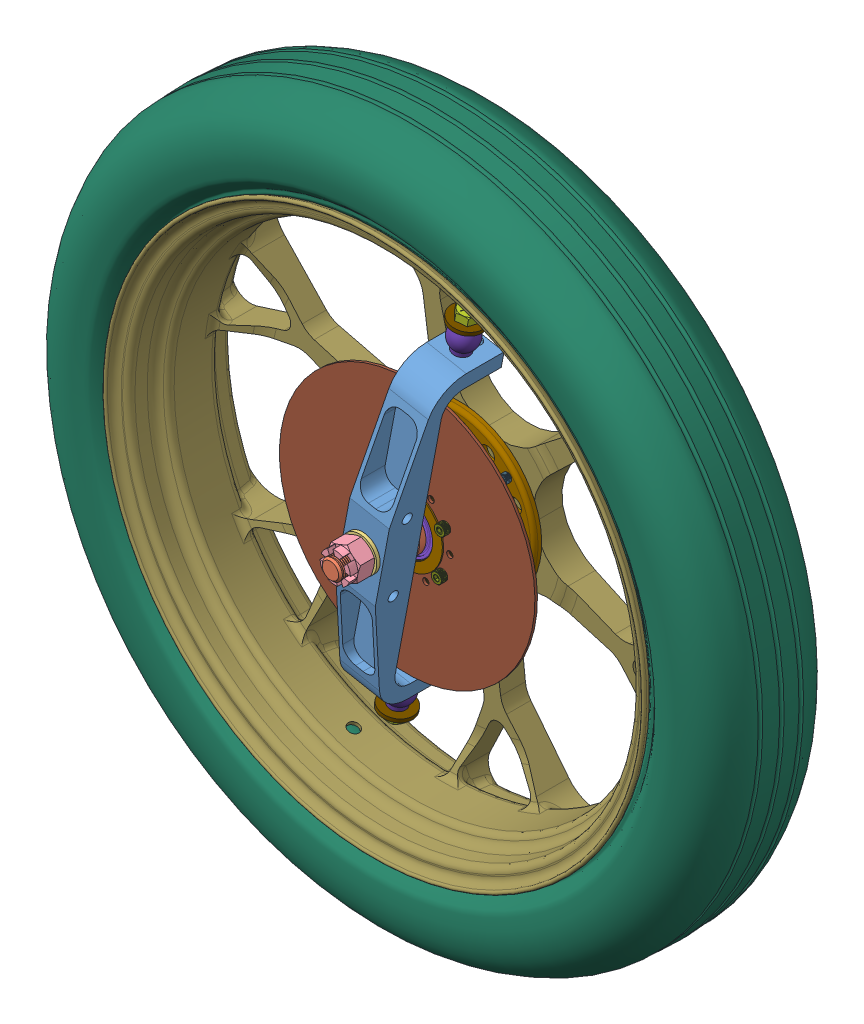
SolidWorks assembly SpindleAssy, configuration Default. Lengths in mm.
Overall size (616.2 616.2 50000).
36 component instances, 18 part files, 73 mates.
Components (placement in the parent):
- Knuckle-1: Knuckle [Default] at (82.0121 130.0239 204.0915) size (78.12 253.33 73.5)
- Spindle_Light-1: Spindle_Light [Default] at (82.0121 130.0239 204.0915) x (0 0 -1) z (0.185408 0.982662 0) size (140.5 34 30)
- M16 98688A121_General Purpose Zinc-Plated Steel Washer-1: M16 98688A121_General Purpose Zinc-Plated Steel Washer [98688A121] at (82.0121 130.0239 232.5915) x (0.99983 -0.018445 0) z (0 0 1) size (28 28 2.7)
- M16x1-5 93760A128_Steel Locknut for Use with Cotter Pins-1: M16x1-5 93760A128_Steel Locknut for Use with Cotter Pins [93760A128] at (82.0121 130.0239 254.2915) x (0.982886 -0.184217 0) z (0 0 1) size (24 27.71 19.76)
- M14 98689A119_General Purpose 18-8 Stainless Steel Washer-1: M14 98689A119_General Purpose 18-8 Stainless Steel Washer [98689A119] at (82.0121 130.0239 138.2415) size (24 24 2.7)
- M14x1-5 93760A127_Steel Locknut for Use with Cotter Pins-1: M14x1-5 93760A127_Steel Locknut for Use with Cotter Pins [93760A127] at (82.0121 130.0239 120.8915) x (-0.661913 -0.74958 0) z (0 0 -1) size (22 25.4 16.76)
- 91257A659_Zinc Yellow-Chromate Plated Hex Head Screw-2: 91257A659_Zinc Yellow-Chromate Plated Hex Head Screw [91257A659] at (58.1191 3.3909 177.4439) x (0.185408 0.982662 0) z (0.110595 -0.020867 0.993646) size (57.6 16.5 14.29)
- 91257A659_Zinc Yellow-Chromate Plated Hex Head Screw-3: 91257A659_Zinc Yellow-Chromate Plated Hex Head Screw [91257A659] at (105.9051 256.6568 177.4439) x (-0.185408 -0.982662 0) z (-0.685297 0.129301 0.716693) size (57.6 16.5 14.29)
- SKF_6004-2Z.stp-1: SKF_6004-2Z.stp [Default] at (82.0121 130.0239 185.0915) x (0 0 1) z (-0.58163 0.813454 0) size (12 42 42)
- Hub5-16-1: Hub5-16 [Default] at (82.0121 130.0239 173.6746) x (-0.944813 0.32761 0) z (0.32761 0.944813 0) size (130 85 130)
- SKF_6003-2Z.stp-1: SKF_6003-2Z.stp [Default] at (82.0121 130.0239 149.5915) x (0 0 -1) z (0.973183 -0.230032 0) size (10 35 35)
- BasicBrakeDisc-1: BasicBrakeDisc [Default] at (82.0121 130.0239 195.0915) x (0.071911 0.997411 0) z (0 0 1) size (190.5 190.5 3.17)
- rimmachined v13.2-1: rimmachined v13.2 [Default] at (82.0121 130.0239 177.3915) x (0 0 -1) z (-0.981935 -0.189217 0) size (93.59 431.57 431.57)
- 92415A381_Zinc-Plated Steel Unthreaded Spacer-2: 92415A381_Zinc-Plated Steel Unthreaded Spacer [92415A381] at (71.0682 186.982 155.2387) size (7.94 7.94 7.21)
- 92415A381_Zinc-Plated Steel Unthreaded Spacer-3: 92415A381_Zinc-Plated Steel Unthreaded Spacer [92415A381] at (27.2129 149.0252 155.2387) size (7.94 7.94 7.21)
- 92415A381_Zinc-Plated Steel Unthreaded Spacer-4: 92415A381_Zinc-Plated Steel Unthreaded Spacer [92415A381] at (38.1569 92.0671 155.2387) size (7.94 7.94 7.21)
- 92415A381_Zinc-Plated Steel Unthreaded Spacer-5: 92415A381_Zinc-Plated Steel Unthreaded Spacer [92415A381] at (92.956 73.0657 155.2387) size (7.94 7.94 7.21)
- 92415A381_Zinc-Plated Steel Unthreaded Spacer-6: 92415A381_Zinc-Plated Steel Unthreaded Spacer [92415A381] at (136.8113 111.0225 155.2387) size (7.94 7.94 7.21)
- 92415A381_Zinc-Plated Steel Unthreaded Spacer-7: 92415A381_Zinc-Plated Steel Unthreaded Spacer [92415A381] at (125.8674 167.9807 155.2387) size (7.94 7.94 7.21)
- 8-32x3-8 92196A192_18-8 Stainless Steel Socket Head Screw-1: 8-32x3-8 92196A192_18-8 Stainless Steel Socket Head Screw [92196A192] at (92.956 73.0657 158.4118) size (6.85 6.85 14.15)
- 8-32x3-8 92196A192_18-8 Stainless Steel Socket Head Screw-2: 8-32x3-8 92196A192_18-8 Stainless Steel Socket Head Screw [92196A192] at (38.1569 92.0671 158.4118) size (6.85 6.85 14.15)
- 8-32x3-8 92196A192_18-8 Stainless Steel Socket Head Screw-3: 8-32x3-8 92196A192_18-8 Stainless Steel Socket Head Screw [92196A192] at (136.8113 111.0225 158.4118) size (6.85 6.85 14.15)
- 8-32x3-8 92196A192_18-8 Stainless Steel Socket Head Screw-4: 8-32x3-8 92196A192_18-8 Stainless Steel Socket Head Screw [92196A192] at (125.8674 167.9807 158.4118) size (6.85 6.85 14.15)
- 8-32x3-8 92196A192_18-8 Stainless Steel Socket Head Screw-5: 8-32x3-8 92196A192_18-8 Stainless Steel Socket Head Screw [92196A192] at (71.0682 186.982 158.4118) size (6.85 6.85 14.15)
- 8-32x3-8 92196A192_18-8 Stainless Steel Socket Head Screw-6: 8-32x3-8 92196A192_18-8 Stainless Steel Socket Head Screw [92196A192] at (27.2129 149.0252 158.4118) size (6.85 6.85 14.15)
- Michelin Tire-1: Michelin Tire [Default] at (82.0121 130.0239 177.3915) x (0 0 1) z (-0.993534 -0.113534 0) size (101.13 556.61 556.61)
- M5x10 91290A224_Alloy Steel Socket Head Screw-1: M5x10 91290A224_Alloy Steel Socket Head Screw [91290A224] at (84.4571 163.9358 194.5915) x (0.901899 0.431946 0) z (0 0 1) size (8.5 8.5 15.31)
- M5x10 91290A224_Alloy Steel Socket Head Screw-2: M5x10 91290A224_Alloy Steel Socket Head Screw [91290A224] at (53.866 149.0973 194.5915) x (-0.609316 -0.792927 0) z (0 0 1) size (8.5 8.5 15.31)
- M5x10 91290A224_Alloy Steel Socket Head Screw-3: M5x10 91290A224_Alloy Steel Socket Head Screw [91290A224] at (112.6032 144.8625 194.5915) x (0.740699 0.671837 0) z (0 0 1) size (8.5 8.5 15.31)
- M5x10 91290A224_Alloy Steel Socket Head Screw-4: M5x10 91290A224_Alloy Steel Socket Head Screw [91290A224] at (110.1583 110.9505 194.5915) x (-0.161403 -0.986889 0) z (0 0 1) size (8.5 8.5 15.31)
- M5x10 91290A224_Alloy Steel Socket Head Screw-5: M5x10 91290A224_Alloy Steel Socket Head Screw [91290A224] at (51.421 115.1853 194.5915) x (0.079005 -0.996874 0) z (0 0 1) size (8.5 8.5 15.31)
- M5x10 91290A224_Alloy Steel Socket Head Screw-6: M5x10 91290A224_Alloy Steel Socket Head Screw [91290A224] at (79.5671 96.1119 194.5915) x (-0.159143 -0.987256 0) z (0 0 1) size (8.5 8.5 15.31)
- BallSuper-Swivel  Joint Rod End6960T231_-1: BallSuper-Swivel  Joint Rod End6960T231_ [6960T231] at (75.3125 -8.1245 178.3098) x (-0.044663 0.008427 0.998967) z (-0.185408 -0.982662 0) size (20.64 20.64 22.23)
- BallSuper-Swivel  Joint Rod End6960T231_-2: BallSuper-Swivel  Joint Rod End6960T231_ [6960T231] at (109.0836 264.3285 196.4178) x (0.978736 -0.184667 -0.089292) z (0.185408 0.982662 0) size (20.64 20.64 22.23)
- 3-8 98029A046_Black-Oxide Steel Oversized Washer-1: 3-8 98029A046_Black-Oxide Steel Oversized Washer [98029A046] at (54.2751 -16.9823 177.4439) x (0.965511 -0.182172 -0.186017) z (0.185408 0.982662 0) size (25.4 25.4 2.98)
- 3-8 98029A046_Black-Oxide Steel Oversized Washer-2: 3-8 98029A046_Black-Oxide Steel Oversized Washer [98029A046] at (109.7491 277.0301 177.4439) x (0.965511 -0.182172 -0.186017) z (0.185408 0.982662 0) size (25.4 25.4 2.98)
Mates (geometry in assembly coordinates):
- Coincident1: coincident anti-aligned: circle of Knuckle-1; circle of Spindle_Light-1
- Concentric1: concentric aligned: circle of Knuckle-1; circle of M16 98688A121_General Purpose Zinc-Plated Steel Washer-1
- Concentric2: concentric aligned: circle of M16 98688A121_General Purpose Zinc-Plated Steel Washer-1; circle of M16x1-5 93760A128_Steel Locknut for Use with Cotter Pins-1
- Coincident2: coincident anti-aligned: plane of Knuckle-1 through (82.0121 130.0239 232.5915) normal (0 0 1); plane of M16 98688A121_General Purpose Zinc-Plated Steel Washer-1 through (82.0121 130.0239 232.5915) normal (0 0 -1)
- Coincident3: coincident anti-aligned: plane of M16 98688A121_General Purpose Zinc-Plated Steel Washer-1 through (82.0121 130.0239 235.2915) normal (0 0 1); plane of M16x1-5 93760A128_Steel Locknut for Use with Cotter Pins-1 through (84.5647 143.6431 235.2915) normal (0 0 -1)
- Parallel1: parallel aligned: plane of Spindle_Light-1 through (82.0121 130.0239 258.0915) normal (0 0 1); plane of M16x1-5 93760A128_Steel Locknut for Use with Cotter Pins-1 through (82.0121 130.0239 248.2915) normal (0 0 1)
- Concentric3: concentric anti-aligned: circle of M14 98689A119_General Purpose 18-8 Stainless Steel Washer-1; circle of M14x1-5 93760A127_Steel Locknut for Use with Cotter Pins-1
- Coincident5: coincident anti-aligned: plane of M14 98689A119_General Purpose 18-8 Stainless Steel Washer-1 through (82.0121 130.0239 136.8915) normal (0 0 -1); plane of M14x1-5 93760A127_Steel Locknut for Use with Cotter Pins-1 through (75.0117 150.8804 136.8915) normal (0 0 1)
- Concentric4: concentric anti-aligned: circle of Spindle_Light-1; circle of M14 98689A119_General Purpose 18-8 Stainless Steel Washer-1
- Perpendicular1: perpendicular: line of Knuckle-1 through (84.6232 230.1587 204.0915) axis (-0.185408 -0.982662 0); line of Spindle_Light-1 through (76.9319 146.2471 204.0915) axis (0.982662 -0.185408 0)
- Concentric5: concentric aligned: circle of Knuckle-1; circle of Super-Swivel Ball Joint Ball End2-1
- Coincident7: coincident anti-aligned: plane of Knuckle-1 through (89.6292 256.6906 232.5915) normal (0.185408 0.982662 0); plane of Super-Swivel Ball Joint Ball End2-1 through (107.5018 254.0508 172.0915) normal (-0.20131 -0.979528 0)
- Concentric6: concentric anti-aligned: circle of Knuckle-1; circle of Super-Swivel Ball Joint Ball End2-2
- Coincident8: coincident anti-aligned: plane of Knuckle-1 through (74.395 3.3572 232.5915) normal (-0.185408 -0.982662 0); plane of Super-Swivel Ball Joint Ball End2-2 through (56.5224 5.997 172.0915) normal (0.20131 0.979528 0)
- Coincident11: coincident anti-aligned: circle of Knuckle-1; circle of SteerArm-1
- Coincident12: coincident anti-aligned: circle of Knuckle-1; circle of SteerArm-1
- Concentric7: concentric anti-aligned: circle of Spindle_Light-1; circle of SKF_6004-2Z.stp-1
- Coincident13: coincident anti-aligned: plane of Spindle_Light-1 through (70.2202 132.2488 197.0915) normal (0 0 -1); plane of SKF_6004-2Z.stp-1 through (90.6347 136.1891 197.0915) normal (0 0 1)
- Coincident14: coincident anti-aligned: plane of SKF_6004-2Z.stp-1 through (98.6066 141.8891 185.0915) normal (0 0 -1); plane of Hub5-16-1 through (64.0607 136.2485 185.0915) normal (0 0 1)
- Concentric8: concentric aligned: cylinder of SKF_6004-2Z.stp-1 through (82.0121 130.0239 235.0915) axis (0 0 1) radius 21; cylinder of Hub5-16-1 through (82.0121 130.0239 1099.7023) axis (0 0 1) radius 21
- Concentric9: concentric anti-aligned: cylinder of Hub5-16-1 through (82.0121 130.0239 1099.7023) axis (0 0 1) radius 17.5; cylinder of SKF_6003-2Z.stp-1 through (82.0121 130.0239 99.5915) axis (0 0 -1) radius 17.5
- Coincident15: coincident anti-aligned: plane of Hub5-16-1 through (67.3675 135.1018 149.5915) normal (0 0 -1); plane of SKF_6003-2Z.stp-1 through (85.9687 146.7626 149.5915) normal (0 0 1)
- Coincident16: coincident anti-aligned: plane of M14 98689A119_General Purpose 18-8 Stainless Steel Washer-1 through (82.0121 130.0239 139.5915) normal (0 0 1); plane of SKF_6003-2Z.stp-1 through (84.0364 138.5879 139.5915) normal (0 0 -1)
- Concentric10: concentric aligned: circle of Hub5-16-1; circle of BasicBrakeDisc-1
- Coincident18: coincident anti-aligned: plane of Hub5-16-1 through (54.6125 139.5246 195.0915) normal (0 0 1); plane of BasicBrakeDisc-1 through (82.0121 130.0239 195.0915) normal (0 0 -1)
- Concentric11: concentric anti-aligned: cylinder of Hub5-16-1 through (82.0121 130.0239 1099.7023) axis (0 0 1) radius 47; cylinder of rimmachined v13.2-1 through (82.0121 130.0239 168.2915) axis (0 0 -1) radius 47.005
- Coincident19: coincident aligned: circle of Hub5-16-1; circle of 92415A381_Zinc-Plated Steel Unthreaded Spacer-5
- Coincident20: coincident aligned: circle of Hub5-16-1; circle of 92415A381_Zinc-Plated Steel Unthreaded Spacer-4
- Coincident21: coincident aligned: circle of Hub5-16-1; circle of 92415A381_Zinc-Plated Steel Unthreaded Spacer-3
- Coincident22: coincident aligned: circle of Hub5-16-1; circle of 92415A381_Zinc-Plated Steel Unthreaded Spacer-2
- Coincident23: coincident aligned: circle of Hub5-16-1; circle of 92415A381_Zinc-Plated Steel Unthreaded Spacer-7
- Coincident24: coincident aligned: circle of Hub5-16-1; circle of 92415A381_Zinc-Plated Steel Unthreaded Spacer-6
- Concentric121: concentric anti-aligned: cylinder of Hub5-16-1 through (92.956 73.0657 151.0915) axis (0 0 1) radius 2.15; cylinder of 8-32x3-8 92196A192_18-8 Stainless Steel Socket Head Screw-1 through (92.956 73.0657 151.5665) axis (0 0 -1) radius 2.0828
- Coincident251: coincident anti-aligned: plane of Hub5-16-1 through (23.4337 150.3357 161.0915) normal (0 0 1); plane of 8-32x3-8 92196A192_18-8 Stainless Steel Socket Head Screw-1 through (89.6985 73.0657 161.0915) normal (0 0 -1)
- Concentric131: concentric anti-aligned: cylinder of Hub5-16-1 through (38.1569 92.0671 151.0915) axis (0 0 1) radius 2.15; cylinder of 8-32x3-8 92196A192_18-8 Stainless Steel Socket Head Screw-2 through (38.1569 92.0671 151.5665) axis (0 0 -1) radius 2.0828
- Coincident261: coincident anti-aligned: plane of Hub5-16-1 through (23.4337 150.3357 161.0915) normal (0 0 1); plane of 8-32x3-8 92196A192_18-8 Stainless Steel Socket Head Screw-2 through (34.8993 92.0671 161.0915) normal (0 0 -1)
- Concentric141: concentric anti-aligned: cylinder of Hub5-16-1 through (136.8113 111.0225 151.0915) axis (0 0 1) radius 2.15; cylinder of 8-32x3-8 92196A192_18-8 Stainless Steel Socket Head Screw-3 through (136.8113 111.0225 151.5665) axis (0 0 -1) radius 2.0828
- Coincident271: coincident anti-aligned: plane of Hub5-16-1 through (23.4337 150.3357 161.0915) normal (0 0 1); plane of 8-32x3-8 92196A192_18-8 Stainless Steel Socket Head Screw-3 through (133.5537 111.0225 161.0915) normal (0 0 -1)
- Concentric151: concentric anti-aligned: cylinder of Hub5-16-1 through (125.8674 167.9807 151.0915) axis (0 0 1) radius 2.15; cylinder of 8-32x3-8 92196A192_18-8 Stainless Steel Socket Head Screw-4 through (125.8674 167.9807 151.5665) axis (0 0 -1) radius 2.0828
- Coincident281: coincident anti-aligned: plane of Hub5-16-1 through (23.4337 150.3357 161.0915) normal (0 0 1); plane of 8-32x3-8 92196A192_18-8 Stainless Steel Socket Head Screw-4 through (122.6098 167.9807 161.0915) normal (0 0 -1)
- Concentric161: concentric anti-aligned: cylinder of Hub5-16-1 through (71.0682 186.982 151.0915) axis (0 0 1) radius 2.15; cylinder of 8-32x3-8 92196A192_18-8 Stainless Steel Socket Head Screw-5 through (71.0682 186.982 151.5665) axis (0 0 -1) radius 2.0828
- Coincident291: coincident anti-aligned: plane of Hub5-16-1 through (23.4337 150.3357 161.0915) normal (0 0 1); plane of 8-32x3-8 92196A192_18-8 Stainless Steel Socket Head Screw-5 through (67.8106 186.982 161.0915) normal (0 0 -1)
- Concentric171: concentric anti-aligned: cylinder of Hub5-16-1 through (27.2129 149.0252 151.0915) axis (0 0 1) radius 2.15; cylinder of 8-32x3-8 92196A192_18-8 Stainless Steel Socket Head Screw-6 through (27.2129 149.0252 151.5665) axis (0 0 -1) radius 2.0828
- Coincident301: coincident anti-aligned: plane of Hub5-16-1 through (23.4337 150.3357 161.0915) normal (0 0 1); plane of 8-32x3-8 92196A192_18-8 Stainless Steel Socket Head Screw-6 through (23.9554 149.0252 161.0915) normal (0 0 -1)
- Tangent1: tangent anti-aligned: plane of rimmachined v13.2-1 through (88.5859 74.7696 150.7915) normal (0.981935 0.189217 0); cylinder of 92415A381_Zinc-Plated Steel Unthreaded Spacer-5 through (92.956 73.0657 151.6669) axis (0 0 1) radius 3.9688
- Coincident31: coincident anti-aligned: plane of Hub5-16-1 through (37.6059 145.4215 155.0915) normal (0 0 -1); plane of rimmachined v13.2-1 through (89.5808 90.7465 155.0915) normal (0 0 1)
- Concentric18: concentric aligned: cone of rimmachined v13.2-1 through (82.0121 130.0239 200.42) axis (0 0 -1); cylinder of Michelin Tire-1 through (82.0121 130.0239 74.6686) axis (0 0 -1) radius 203
- Coincident32: coincident anti-aligned: plane of rimmachined v13.2-1 through (82.0121 130.0239 177.3915) normal (0 0 -1); plane of Michelin Tire-1 through (82.0121 130.0239 177.3915) normal (0 0 1)
- Concentric19: concentric anti-aligned: cylinder of Hub5-16-1 through (67.1735 160.615 185.0915) axis (0 0 1) radius 2; cylinder of BasicBrakeDisc-1 through (67.1735 160.615 197.0915) axis (0 0 -1) radius 2.497
- Concentric20: concentric anti-aligned: circle of BasicBrakeDisc-1; circle of M5x10 91290A224_Alloy Steel Socket Head Screw-2
- Coincident33: coincident anti-aligned: plane of BasicBrakeDisc-1 through (82.0121 130.0239 197.0915) normal (0 0 1); plane of M5x10 91290A224_Alloy Steel Socket Head Screw-2 through (56.3032 152.269 197.0915) normal (0 0 -1)
- Concentric21: concentric anti-aligned: circle of BasicBrakeDisc-1; circle of M5x10 91290A224_Alloy Steel Socket Head Screw-1
- Concentric22: concentric anti-aligned: circle of BasicBrakeDisc-1; circle of M5x10 91290A224_Alloy Steel Socket Head Screw-3
- Concentric23: concentric anti-aligned: circle of BasicBrakeDisc-1; circle of M5x10 91290A224_Alloy Steel Socket Head Screw-4
- Concentric24: concentric anti-aligned: circle of BasicBrakeDisc-1; circle of M5x10 91290A224_Alloy Steel Socket Head Screw-6
- Concentric25: concentric anti-aligned: circle of BasicBrakeDisc-1; circle of M5x10 91290A224_Alloy Steel Socket Head Screw-5
- Coincident34: coincident anti-aligned: plane of BasicBrakeDisc-1 through (82.0121 130.0239 197.0915) normal (0 0 1); plane of M5x10 91290A224_Alloy Steel Socket Head Screw-1 through (80.8495 162.2081 197.0915) normal (0 0 -1)
- Coincident36: coincident anti-aligned: plane of BasicBrakeDisc-1 through (82.0121 130.0239 197.0915) normal (0 0 1); plane of M5x10 91290A224_Alloy Steel Socket Head Screw-3 through (109.6404 142.1751 197.0915) normal (0 0 -1)
- Coincident37: coincident anti-aligned: plane of BasicBrakeDisc-1 through (82.0121 130.0239 197.0915) normal (0 0 1); plane of M5x10 91290A224_Alloy Steel Socket Head Screw-5 through (51.105 119.1728 197.0915) normal (0 0 -1)
- Coincident38: coincident anti-aligned: plane of BasicBrakeDisc-1 through (82.0121 130.0239 197.0915) normal (0 0 1); plane of M5x10 91290A224_Alloy Steel Socket Head Screw-6 through (80.2037 100.0609 197.0915) normal (0 0 -1)
- Coincident39: coincident anti-aligned: plane of BasicBrakeDisc-1 through (82.0121 130.0239 197.0915) normal (0 0 1); plane of M5x10 91290A224_Alloy Steel Socket Head Screw-4 through (110.8039 114.898 197.0915) normal (0 0 -1)
- Coincident302: coincident anti-aligned: plane of Knuckle-1 through (89.6292 256.6906 232.5915) normal (0.185408 0.982662 0); plane of BallSuper-Swivel  Joint Rod End6960T231_-2 through (105.3518 253.724 177.4439) normal (-0.185408 -0.982662 0)
- Coincident303: coincident anti-aligned: plane of Knuckle-1 through (74.395 3.3572 232.5915) normal (-0.185408 -0.982662 0); plane of BallSuper-Swivel  Joint Rod End6960T231_-1 through (58.6725 6.3237 177.4439) normal (0.185408 0.982662 0)
- Concentric174: concentric aligned: cylinder of Knuckle-1 through (57.5915 0.5946 177.4439) axis (0.185408 0.982662 0) radius 4.7625; cylinder of BallSuper-Swivel  Joint Rod End6960T231_-2 through (105.4989 254.504 177.4439) axis (0.185408 0.982662 0) radius 4.7625
- Concentric175: concentric anti-aligned: cylinder of Knuckle-1 through (57.5915 0.5946 177.4439) axis (0.185408 0.982662 0) radius 4.7625; cylinder of BallSuper-Swivel  Joint Rod End6960T231_-1 through (58.5253 5.5437 177.4439) axis (-0.185408 -0.982662 0) radius 4.7625
- Concentric176: concentric anti-aligned: cylinder of 91257A659_Zinc Yellow-Chromate Plated Hex Head Screw-2 through (53.9984 -18.4487 177.4439) axis (0.185408 0.982662 0) radius 4.7625; cylinder of BallSuper-Swivel  Joint Rod End6960T231_-1 through (58.5253 5.5437 177.4439) axis (-0.185408 -0.982662 0) radius 4.7625
- Concentric177: concentric anti-aligned: cylinder of 91257A659_Zinc Yellow-Chromate Plated Hex Head Screw-2 through (53.9984 -18.4487 177.4439) axis (0.185408 0.982662 0) radius 4.7625; cylinder of 3-8 98029A046_Black-Oxide Steel Oversized Washer-1 through (54.5518 -15.516 177.4439) axis (-0.185408 -0.982662 0) radius 5.1562
- Coincident304: coincident anti-aligned: plane of BallSuper-Swivel  Joint Rod End6960T231_-1 through (54.5518 -15.516 177.4439) normal (-0.185408 -0.982662 0); plane of 3-8 98029A046_Black-Oxide Steel Oversized Washer-1 through (54.5518 -15.516 177.4439) normal (0.185408 0.982662 0)
- Coincident305: coincident anti-aligned: plane of 91257A659_Zinc Yellow-Chromate Plated Hex Head Screw-2 through (50.7613 -17.8379 185.0065) normal (0.185408 0.982662 0); plane of 3-8 98029A046_Black-Oxide Steel Oversized Washer-1 through (53.9984 -18.4487 177.4439) normal (-0.185408 -0.982662 0)
- Concentric178: concentric aligned: circle of BallSuper-Swivel  Joint Rod End6960T231_-2; circle of 3-8 98029A046_Black-Oxide Steel Oversized Washer-2
- Coincident306: coincident anti-aligned: plane of BallSuper-Swivel  Joint Rod End6960T231_-2 through (109.4725 275.5637 177.4439) normal (0.185408 0.982662 0); plane of 3-8 98029A046_Black-Oxide Steel Oversized Washer-2 through (109.4725 275.5637 177.4439) normal (-0.185408 -0.982662 0)
- Concentric179: concentric anti-aligned: cylinder of 91257A659_Zinc Yellow-Chromate Plated Hex Head Screw-3 through (110.0258 278.4965 177.4439) axis (-0.185408 -0.982662 0) radius 4.7625; cylinder of BallSuper-Swivel  Joint Rod End6960T231_-2 through (105.4989 254.504 177.4439) axis (0.185408 0.982662 0) radius 4.7625
- Coincident307: coincident anti-aligned: plane of 91257A659_Zinc Yellow-Chromate Plated Hex Head Screw-3 through (108.0349 278.8721 185.4402) normal (-0.185408 -0.982662 0); plane of 3-8 98029A046_Black-Oxide Steel Oversized Washer-2 through (110.0258 278.4965 177.4439) normal (0.185408 0.982662 0)
